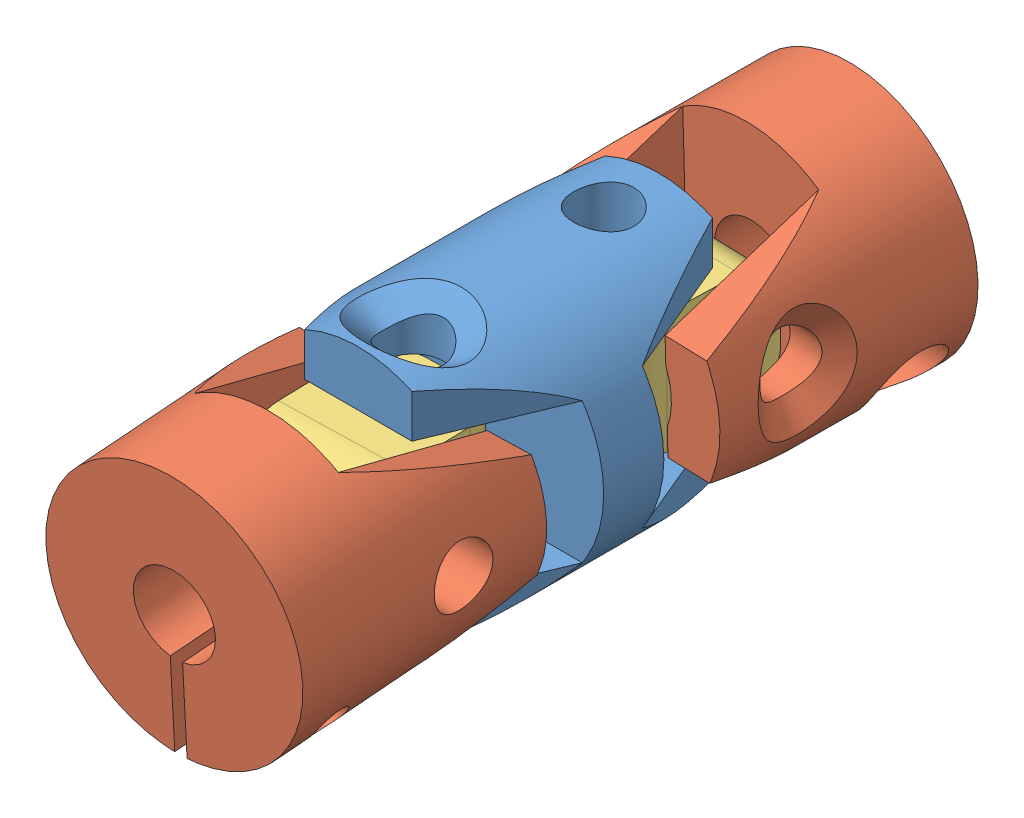
SolidWorks assembly UJ_assy_8mm, configuration Default. Lengths in mm.
Overall size (25.99 26.28 69.65).
5 component instances, 3 part files, 8 mates.
Components (placement in the parent):
- UJ_centre_8mm-1: UJ_centre_8mm [Default] at origin size (25 25.2 30)
- UJ_End_8mm-1: UJ_End_8mm [Default] at (0.373 0.1048 -28.9928) x (0.000814 -0.999657 -0.026186) z (-0.031078 -0.026198 0.999174) size (24.99 25.1 25)
- UJ_End_8mm-2: UJ_End_8mm [Default] at (0.3042 -0.2135 13.9904) x (-0.001354 -0.998575 -0.053358) z (-0.025324 0.053375 -0.998253) size (24.99 25.1 25)
- UJ_block_8mm-1: UJ_block_8mm [Default] at (0.1014 0 5.9987) x (0.999678 0 -0.02536) z (0.02536 0 0.999678) size (12 12 15)
- UJ_block_8mm-2: UJ_block_8mm [Default] at (0.1244 0 -20.9981) x (-0.999517 0 -0.031089) z (0.031089 0 -0.999517) size (12 12 15)
Mates (geometry in assembly coordinates):
- Concentric1: concentric aligned: cylinder of UJ_centre_8mm-1; cylinder of UJ_block_8mm-1
- Concentric2: concentric anti-aligned: cylinder of UJ_End_8mm-2; cylinder of UJ_block_8mm-1
- Coincident4: coincident anti-aligned: plane of UJ_End_8mm-2 through (0.3042 -0.2135 13.9904) normal (-0.999678 0 0.02536); plane of UJ_block_8mm-1 through (0.1014 0 5.9987) normal (0.999678 0 -0.02536)
- Coincident7: coincident aligned: plane of UJ_centre_8mm-1 through (0 0 0) normal (0 1 0); plane of UJ_block_8mm-1 through (0.1014 0 5.9987) normal (0 1 0)
- Concentric3: concentric aligned: cylinder of UJ_centre_8mm-1; cylinder of UJ_block_8mm-2
- Concentric4: concentric anti-aligned: cylinder of UJ_End_8mm-1; cylinder of UJ_block_8mm-2
- Coincident8: coincident aligned: plane of UJ_centre_8mm-1 through (0 0 0) normal (0 1 0); plane of UJ_block_8mm-2 through (0.1244 0 -20.9981) normal (0 1 0)
- Coincident12: coincident anti-aligned: plane of UJ_End_8mm-1 through (0.373 0.1048 -28.9928) normal (0.999517 0 0.031089); plane of UJ_block_8mm-2 through (0.1244 0 -20.9981) normal (-0.999517 0 -0.031089)
